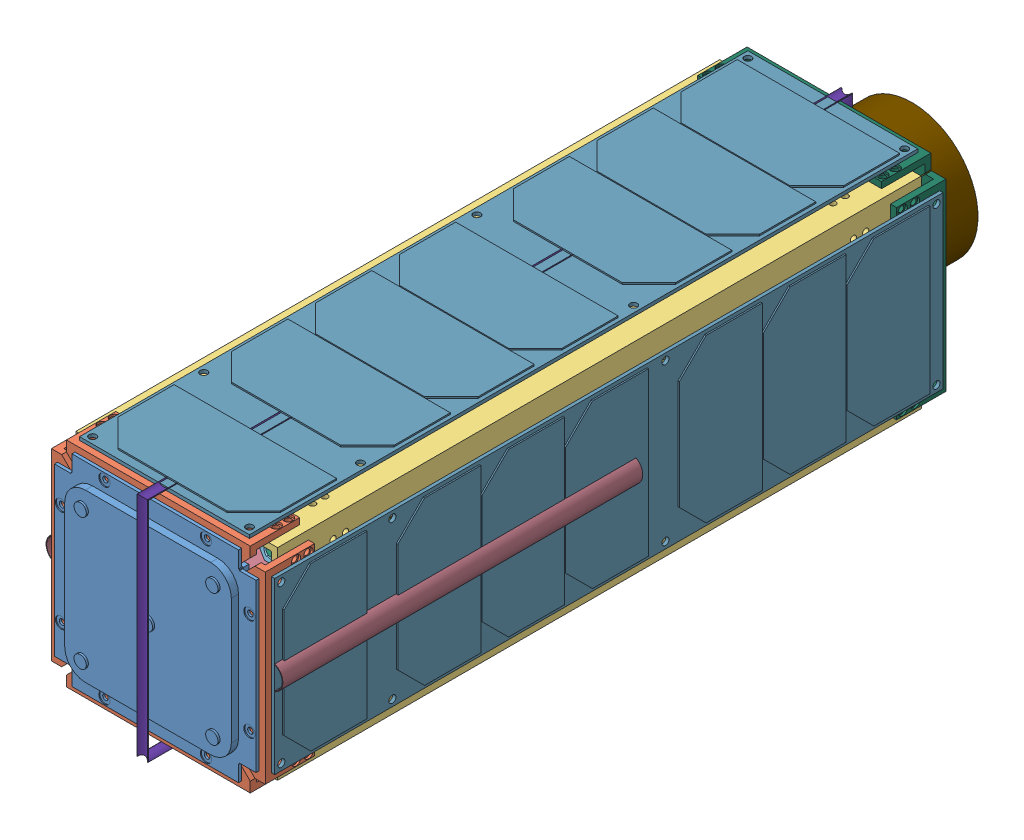
SolidWorks assembly RADIO Stowed, configuration Default. Lengths in mm.
Overall size (115.59 110.99 374.49).
77 component instances, 18 part files, 143 mates.
Components (placement in the parent):
- Nanocom Antenna-1: Nanocom Antenna [Default] at (54.7327 27.087 80.9297) size (98 98 11)
- Top Sipport-1: Top Sipport [Default] at (83.9034 50.4516 80.9297) x (0 -1 0) z (0 0 -1) size (89.4 11 24)
- Top Sipport-2: Top Sipport [Default] at (-15.8818 37.5538 80.9297) x (0 1 0) z (0 0 -1) size (89.4 11 24)
- Top Sipport-3: Top Sipport [Default] at (27.5619 93.8953 80.9297) x (1 0 0) z (0 0 -1) size (89.4 11 24)
- Top Sipport-4: Top Sipport [Default] at (40.4598 -5.8899 80.9297) x (-1 0 0) z (0 0 -1) size (89.4 11 24)
- Support-1: Support [Default] at (-14.9892 90.3455 -221.7132) x (0 -1 0) z (1 0 0) size (18 313 15)
- Support-2: Support [Default] at (-12.332 -4.9973 -221.7132) x (1 0 0) z (0 1 0) size (18 313 15)
- Support-3: Support [Default] at (80.3537 93.0027 -221.7132) x (-1 0 0) z (0 -1 0) size (18 313 15)
- Support-4: Support [Default] at (83.0108 -2.3402 -221.7132) x (0 1 0) z (-1 0 0) size (18 313 15)
- Top Plate2-1: Top Plate2 [Default] at (13.317 21.6849 56.9297) x (-1 0 0) z (0 0 -1) size (92 92 23)
- Nut-1: Nut [Default] at (-1.4892 79.5027 56.9297) size (11.55 10 5.32)
- Nut-2: Nut [Default] at (69.5108 8.5027 56.9297) x (0.821931 0.569587 0) z (0 0 1) size (11.55 10 5.32)
- Nut-3: Nut [Default] at (69.5108 79.5027 56.9297) size (11.55 10 5.32)
- Nut-4: Nut [Default] at (-1.4892 8.5027 56.9297) size (11.55 10 5.32)
- Threaded Rod2-1: Threaded Rod2 [Default] at (69.5108 8.5027 -231.0703) size (6.4 7.01 294.26)
- Threaded Rod2-2: Threaded Rod2 [Default] at (-1.4892 8.5027 -231.0703) size (6.4 7.01 294.26)
- Threaded Rod2-3: Threaded Rod2 [Default] at (-1.4892 79.5027 -231.0703) size (6.4 7.01 294.26)
- Threaded Rod2-4: Threaded Rod2 [Default] at (69.5108 79.5027 -231.0703) size (6.4 7.01 294.26)
- Mid Plate-1: Mid Plate [Default] at (4.649 54.0261 25.9297) size (86 86 3)
- Nut-5: Nut [Default] at (-1.4892 8.5027 20.9297) x (0.999286 -0.037791 0) z (0 0 1) size (11.55 10 5.32)
- Nut-6: Nut [Default] at (-1.4892 8.5027 28.9297) size (11.55 10 5.32)
- Nut-7: Nut [Default] at (69.5108 8.5027 28.9297) size (11.55 10 5.32)
- Nut-8: Nut [Default] at (69.5108 8.5027 20.9297) x (0.921379 0.388666 0) z (0 0 1) size (11.55 10 5.32)
- Nut-9: Nut [Default] at (69.5108 79.5027 28.9297) size (11.55 10 5.32)
- Nut-10: Nut [Default] at (-1.4892 79.5027 28.9297) size (11.55 10 5.32)
- Nut-11: Nut [Default] at (69.5108 79.5027 20.9297) x (0.963517 0.267648 0) z (0 0 1) size (11.55 10 5.32)
- Nut-12: Nut [Default] at (-1.4892 79.5027 20.9297) x (0.997929 0.06432 0) z (0 0 1) size (11.55 10 5.32)
- SDR-1: SDR [Default] at (37.1692 34.198 30.9297) size (65 40 16.8)
- TTC Radio-1: TTC Radio [Default] at (48.3672 78.5027 28.9297) x (0 1 0) z (0 0 1) size (19.7 16 5)
- Raspberry Pi-1: Raspberry Pi [Default] at (63.5108 49.6464 -55.0703) size (66 30.48 5)
- TTC Circuit-1: TTC Circuit [Default] at (24.4431 25.9578 10.9297) size (80 50 10)
- Battery-1: Battery [Default] at (21.7415 31.358 -37.0703) size (70.1 42.59 38.1)
- Tape Antenna-3: Tape Antenna [Default] at (-17.3053 44.2096 -97.0703) x (-0.035253 -0.999378 0) z (0 0 1) size (11.67 4.21 175)
- Tape Antenna-4: Tape Antenna [Default] at (85.299 43.4652 -97.0703) x (0.030207 0.999544 0) z (0 0 1) size (11.67 4.21 175)
- Mid Plate-2: Mid Plate [Default] at (4.649 54.0261 7.9297) size (86 86 3)
- Nut-13: Nut [Default] at (-1.4892 8.5027 10.9297) size (11.55 10 5.32)
- Nut-14: Nut [Default] at (69.5108 79.5027 10.9297) size (11.55 10 5.32)
- Nut-15: Nut [Default] at (-1.4892 8.5027 2.9297) size (11.55 10 5.32)
- Nut-16: Nut [Default] at (-1.4892 79.5027 10.9297) size (11.55 10 5.32)
- Nut-17: Nut [Default] at (-1.4892 79.5027 2.9297) size (11.55 10 5.32)
- Nut-18: Nut [Default] at (69.5108 8.5027 2.9297) size (11.55 10 5.32)
- Nut-19: Nut [Default] at (69.5108 8.5027 10.9297) size (11.55 10 5.32)
- Nut-20: Nut [Default] at (69.5108 79.5027 2.9297) size (11.55 10 5.32)
- Mid Plate-3: Mid Plate [Default] at (4.649 54.0261 -40.0703) size (86 86 3)
- Nut-21: Nut [Default] at (69.5108 79.5027 -37.0703) size (11.55 10 5.32)
- Nut-22: Nut [Default] at (-1.4892 8.5027 -40.0703) x (-0.923728 -0.383049 0) z (0 0 -1) size (11.55 10 5.32)
- Nut-23: Nut [Default] at (-1.4892 79.5027 -40.0703) x (-0.923728 -0.383049 0) z (0 0 -1) size (11.55 10 5.32)
- Nut-24: Nut [Default] at (69.5108 8.5027 -37.0703) size (11.55 10 5.32)
- Nut-25: Nut [Default] at (69.5108 79.5027 -40.0703) x (-0.923728 -0.383049 0) z (0 0 -1) size (11.55 10 5.32)
- Nut-26: Nut [Default] at (69.5108 8.5027 -40.0703) x (-0.923728 -0.383049 0) z (0 0 -1) size (11.55 10 5.32)
- Nut-27: Nut [Default] at (-1.4892 8.5027 -37.0703) size (11.55 10 5.32)
- Nut-28: Nut [Default] at (-1.4892 79.5027 -37.0703) size (11.55 10 5.32)
- Nut-29: Nut [Default] at (-1.4892 8.5027 -63.0703) size (11.55 10 5.32)
- Nut-30: Nut [Default] at (69.5108 79.5027 -63.0703) size (11.55 10 5.32)
- Nut-31: Nut [Default] at (69.5108 8.5027 -63.0703) size (11.55 10 5.32)
- Nut-32: Nut [Default] at (-1.4892 8.5027 -55.0703) size (11.55 10 5.32)
- Nut-33: Nut [Default] at (-1.4892 79.5027 -55.0703) size (11.55 10 5.32)
- Nut-34: Nut [Default] at (69.5108 8.5027 -55.0703) size (11.55 10 5.32)
- Nut-35: Nut [Default] at (-1.4892 79.5027 -63.0703) size (11.55 10 5.32)
- Nut-36: Nut [Default] at (69.5108 79.5027 -55.0703) size (11.55 10 5.32)
- Mid Plate-4: Mid Plate [Default] at (4.649 54.0261 -58.0703) size (86 86 3)
- Top Plate2-2: Top Plate2 [Default] at (54.7047 21.6849 -226.0703) size (92 92 23)
- Nut-37: Nut [Default] at (69.5108 8.5027 -226.0703) x (-0.923728 -0.383049 0) z (0 0 -1) size (11.55 10 5.32)
- Nut-38: Nut [Default] at (69.5108 79.5027 -226.0703) x (-0.923728 -0.383049 0) z (0 0 -1) size (11.55 10 5.32)
- Nut-39: Nut [Default] at (-1.4892 8.5027 -226.0703) x (-0.923728 -0.383049 0) z (0 0 -1) size (11.55 10 5.32)
- Nut-40: Nut [Default] at (-1.4892 79.5027 -226.0703) x (-0.923728 -0.383049 0) z (0 0 -1) size (11.55 10 5.32)
- 3U Panel-1: 3U Panel [Default] at (-17.9892 -8.6653 1.9441) x (0 -1 0) z (-1 0 0) size (82.6 325 2.3)
- 3U Panel-5: 3U Panel [Default] at (86.6788 -7.9973 1.9441) x (1 0 0) z (0 -1 0) size (82.6 325 2.3)
- 3U Panel-6: 3U Panel [Default] at (86.0108 96.6707 1.9441) x (0 1 0) z (1 0 0) size (82.6 325 2.3)
- 3U Panel-7: 3U Panel [Default] at (-18.6571 96.0027 1.9441) x (-1 0 0) z (0 1 0) size (82.6 325 2.3)
- Top Support Solar Panel-1: Top Support Solar Panel [Default] at (27.5619 -3.8899 -250.0703) size (89.4 13 24)
- Top Support Solar Panel-2: Top Support Solar Panel [Default] at (81.9034 37.5538 -250.0703) x (0 1 0) z (0 0 1) size (89.4 13 24)
- Top Support Solar Panel-3: Top Support Solar Panel [Default] at (40.4598 91.8953 -250.0703) x (-1 0 0) z (0 0 1) size (89.4 13 24)
- Top Support Solar Panel-4: Top Support Solar Panel [Default] at (-13.8818 50.4516 -250.0703) x (0 -1 0) z (0 0 1) size (89.4 13 24)
- 1U Panel-1: 1U Panel [Default] at (10.1282 49.1305 -250.0703) x (-1 0 0) z (0 0 -1) size (98 98 2.3)
- Undeployed Boom-1: Undeployed Boom [Default] at (33.6808 70.7812 -106.8653) x (0 0 -1) z (1 0 0) size (342.69 110.69 5.53)
- Mass-1: Mass [Default] at (33.6036 44.7293 -286.0703) size (64 64 36)
Mates (geometry in assembly coordinates):
- Coincident1: coincident: circle of Nanocom Antenna-1; circle of Top Sipport-4
- Coincident2: coincident: circle of Nanocom Antenna-1; circle of Top Sipport-4
- Coincident3: coincident: circle of Nanocom Antenna-1; circle of Top Sipport-2
- Coincident4: coincident: circle of Nanocom Antenna-1; circle of Top Sipport-2
- Coincident5: coincident: circle of Nanocom Antenna-1; circle of Top Sipport-3
- Coincident6: coincident: circle of Nanocom Antenna-1; circle of Top Sipport-3
- Coincident7: coincident: circle of Nanocom Antenna-1; circle of Top Sipport-1
- Coincident8: coincident: circle of Nanocom Antenna-1; circle of Top Sipport-1
- Coincident9: coincident: circle of Top Sipport-2; circle of Support-1
- Coincident10: coincident: circle of Top Sipport-3; circle of Support-1
- Coincident11: coincident: circle of Top Sipport-3; circle of Support-3
- Coincident12: coincident: circle of Top Sipport-1; circle of Support-3
- Coincident13: coincident: circle of Top Sipport-2; circle of Support-2
- Coincident14: coincident: circle of Top Sipport-4; circle of Support-2
- Coincident16: coincident: circle of Top Sipport-4; circle of Support-4
- Coincident17: coincident: circle of Top Sipport-1; circle of Support-4
- Coincident20: coincident: circle of Support-1; circle of Top Plate2-1
- Coincident21: coincident: circle of Support-2; circle of Top Plate2-1
- Coincident22: coincident: circle of Top Plate2-1; circle of Nut-3
- Coincident23: coincident: circle of Top Plate2-1; circle of Nut-1
- Coincident24: coincident: circle of Top Plate2-1; circle of Nut-4
- Coincident25: coincident: circle of Top Plate2-1; circle of Nut-2
- Concentric1: concentric: circle of Top Plate2-1; circle of Threaded Rod2-1
- Coincident26: coincident: plane of Nut-2 through (69.5108 8.5027 61.9297) normal (0 0 1); plane of Threaded Rod2-1 through (69.5108 8.5027 61.9297) normal (0 0 1)
- Concentric2: concentric: circle of Top Plate2-1; circle of Threaded Rod2-4
- Coincident27: coincident: plane of Nut-3 through (69.5108 79.5027 61.9297) normal (0 0 1); plane of Threaded Rod2-4 through (69.5108 79.5027 61.9297) normal (0 0 1)
- Concentric3: concentric: circle of Top Plate2-1; circle of Threaded Rod2-2
- Coincident28: coincident: plane of Nut-4 through (-1.4892 8.5027 61.9297) normal (0 0 1); plane of Threaded Rod2-2 through (-1.4892 8.5027 61.9297) normal (0 0 1)
- Concentric4: concentric: circle of Top Plate2-1; circle of Threaded Rod2-3
- Coincident29: coincident: plane of Nut-1 through (-1.4892 79.5027 61.9297) normal (0 0 1); plane of Threaded Rod2-3 through (-1.4892 79.5027 61.9297) normal (0 0 1)
- Concentric5: concentric: circle of Threaded Rod2-4; circle of Mid Plate-1
- Concentric6: concentric: circle of Threaded Rod2-2; circle of Mid Plate-1
- Concentric7: concentric: circle of Threaded Rod2-2; circle of Nut-6
- Coincident30: coincident: plane of Mid Plate-1 through (4.649 54.0261 28.9297) normal (0 0 1); plane of Nut-6 through (-1.4892 8.5027 28.9297) normal (0 0 -1)
- Concentric8: concentric: circle of Threaded Rod2-2; circle of Nut-5
- Coincident31: coincident: plane of Mid Plate-1 through (4.649 54.0261 25.9297) normal (0 0 -1); plane of Nut-5 through (-1.4892 8.5027 25.9297) normal (0 0 1)
- Concentric9: concentric: circle of Threaded Rod2-1; circle of Nut-7
- Coincident32: coincident: plane of Mid Plate-1 through (4.649 54.0261 28.9297) normal (0 0 1); plane of Nut-7 through (69.5108 8.5027 28.9297) normal (0 0 -1)
- Concentric10: concentric: circle of Threaded Rod2-1; circle of Nut-8
- Coincident33: coincident: plane of Mid Plate-1 through (4.649 54.0261 25.9297) normal (0 0 -1); plane of Nut-8 through (69.5108 8.5027 25.9297) normal (0 0 1)
- Concentric11: concentric: circle of Threaded Rod2-4; circle of Nut-9
- Coincident34: coincident: plane of Mid Plate-1 through (4.649 54.0261 28.9297) normal (0 0 1); plane of Nut-9 through (69.5108 79.5027 28.9297) normal (0 0 -1)
- Concentric12: concentric: circle of Threaded Rod2-3; circle of Nut-10
- Coincident35: coincident: plane of Mid Plate-1 through (4.649 54.0261 28.9297) normal (0 0 1); plane of Nut-10 through (-1.4892 79.5027 28.9297) normal (0 0 -1)
- Concentric13: concentric: circle of Threaded Rod2-4; circle of Nut-11
- Coincident36: coincident: plane of Mid Plate-1 through (4.649 54.0261 25.9297) normal (0 0 -1); plane of Nut-11 through (69.5108 79.5027 25.9297) normal (0 0 1)
- Concentric14: concentric: circle of Threaded Rod2-3; circle of Nut-12
- Coincident37: coincident: plane of Mid Plate-1 through (4.649 54.0261 25.9297) normal (0 0 -1); plane of Nut-12 through (-1.4892 79.5027 25.9297) normal (0 0 1)
- Distance1: distance = 25 mm: plane of Mid Plate-1 through (4.649 54.0261 28.9297) normal (0 0 1); plane of Top Plate2-1 through (13.317 21.6849 53.9297) normal (0 0 -1)
- Coincident39: coincident: plane of Mid Plate-1 through (4.649 54.0261 28.9297) normal (0 0 1); plane of SDR-1 through (37.1692 34.198 28.9297) normal (0 0 -1)
- Distance4: distance = 12 mm: line of SDR-1 through (65.0108 16.0027 28.9297) axis (0 1 0); line of Mid Plate-1 through (77.0108 4.0027 28.9297) axis (0 1 0)
- Distance5: distance = 15 mm: line of SDR-1 through (0.0108 16.0027 28.9297) axis (1 0 0); line of Mid Plate-1 through (-5.9892 1.0027 28.9297) axis (1 0 0)
- Coincident46: coincident: plane of Mid Plate-1 through (4.649 54.0261 28.9297) normal (0 0 1); plane of TTC Radio-1 through (48.3672 78.5027 28.9297) normal (0 0 -1)
- Distance8: distance = 20 mm: plane of TTC Radio-1 through (57.0108 78.5027 30.9297) normal (1 0 0); plane of Mid Plate-1 through (77.0108 4.0027 28.9297) normal (1 0 0)
- Distance9: distance = 5 mm: plane of TTC Radio-1 through (48.3672 82.0027 30.9297) normal (0 1 0); line of Mid Plate-1 through (74.0108 87.0027 28.9297) axis (-1 0 0)
- Coincident53: coincident: plane of TTC Circuit-1 through (24.4431 25.9578 10.9297) normal (0 0 -1); plane of Mid Plate-2 through (4.649 54.0261 10.9297) normal (0 0 1)
- Distance10: distance = 5 mm: line of TTC Circuit-1 through (-4.4066 66.0027 12.9297) axis (0 -1 0); line of Mid Plate-2 through (-8.9892 84.0027 10.9297) axis (0 -1 0)
- Distance13: distance = 21.095 mm: line of TTC Circuit-1 through (75.5934 66.0027 12.9297) axis (-1 0 0); line of Mid Plate-2 through (74.0108 87.0027 10.9297) axis (-1 0 0)
- Concentric16: concentric: circle of Threaded Rod2-2; circle of Mid Plate-2
- Concentric18: concentric: circle of Threaded Rod2-4; circle of Mid Plate-2
- Concentric19: concentric: circle of Threaded Rod2-4; circle of Nut-14
- Coincident59: coincident: plane of Mid Plate-2 through (4.649 54.0261 10.9297) normal (0 0 1); plane of Nut-14 through (69.5108 79.5027 10.9297) normal (0 0 -1)
- Concentric20: concentric: circle of Threaded Rod2-4; circle of Nut-20
- Coincident60: coincident: plane of Mid Plate-2 through (4.649 54.0261 7.9297) normal (0 0 -1); plane of Nut-20 through (69.5108 79.5027 7.9297) normal (0 0 1)
- Concentric21: concentric: circle of Threaded Rod2-1; circle of Nut-19
- Coincident61: coincident: plane of Mid Plate-2 through (4.649 54.0261 10.9297) normal (0 0 1); plane of Nut-19 through (69.5108 8.5027 10.9297) normal (0 0 -1)
- Concentric22: concentric: circle of Threaded Rod2-1; circle of Nut-18
- Coincident62: coincident: plane of Mid Plate-2 through (4.649 54.0261 7.9297) normal (0 0 -1); plane of Nut-18 through (69.5108 8.5027 7.9297) normal (0 0 1)
- Concentric23: concentric: circle of Threaded Rod2-2; circle of Nut-13
- Coincident63: coincident: plane of Mid Plate-2 through (4.649 54.0261 10.9297) normal (0 0 1); plane of Nut-13 through (-1.4892 8.5027 10.9297) normal (0 0 -1)
- Concentric24: concentric: circle of Threaded Rod2-2; circle of Nut-15
- Coincident64: coincident: plane of Mid Plate-2 through (4.649 54.0261 7.9297) normal (0 0 -1); plane of Nut-15 through (-1.4892 8.5027 7.9297) normal (0 0 1)
- Concentric25: concentric: circle of Threaded Rod2-3; circle of Nut-16
- Coincident65: coincident: plane of Mid Plate-2 through (4.649 54.0261 10.9297) normal (0 0 1); plane of Nut-16 through (-1.4892 79.5027 10.9297) normal (0 0 -1)
- Concentric26: concentric: circle of Threaded Rod2-3; circle of Nut-17
- Coincident66: coincident: plane of Mid Plate-2 through (4.649 54.0261 7.9297) normal (0 0 -1); plane of Nut-17 through (-1.4892 79.5027 7.9297) normal (0 0 1)
- Distance14: distance = 15 mm: plane of Mid Plate-2 through (4.649 54.0261 10.9297) normal (0 0 1); plane of Mid Plate-1 through (4.649 54.0261 25.9297) normal (0 0 -1)
- Coincident68: coincident: circle of Mid Plate-3; circle of Nut-21
- Coincident69: coincident: circle of Mid Plate-3; circle of Nut-24
- Coincident70: coincident: circle of Mid Plate-3; circle of Nut-27
- Coincident71: coincident: circle of Mid Plate-3; circle of Nut-28
- Coincident72: coincident: circle of Mid Plate-3; circle of Nut-25
- Coincident73: coincident: circle of Mid Plate-3; circle of Nut-23
- Coincident74: coincident: circle of Mid Plate-3; circle of Nut-22
- Coincident76: coincident: circle of Mid Plate-3; circle of Nut-26
- Coincident77: coincident: plane of Battery-1 through (21.7415 31.358 -37.0703) normal (0 0 -1); plane of Mid Plate-3 through (4.649 54.0261 -37.0703) normal (0 0 1)
- Distance16: distance = 30 mm: line of Battery-1 through (57.8687 57.4223 -32.0703) axis (-1 0 0); line of Mid Plate-3 through (74.0108 87.0027 -37.0703) axis (-1 0 0)
- Distance17: distance = 15 mm: line of Battery-1 through (62.8687 24.8323 -32.0703) axis (0 1 0); line of Mid Plate-3 through (77.0108 4.0027 -37.0703) axis (0 1 0)
- Concentric27: concentric: circle of Threaded Rod2-2; circle of Nut-27
- Concentric28: concentric: circle of Threaded Rod2-4; circle of Nut-21
- Distance18: distance = 45 mm: plane of Mid Plate-3 through (4.649 54.0261 -37.0703) normal (0 0 1); plane of Mid Plate-2 through (4.649 54.0261 7.9297) normal (0 0 -1)
- Coincident83: coincident: plane of Raspberry Pi-1 through (63.5108 49.6464 -55.0703) normal (0 0 -1); plane of Mid Plate-4 through (4.649 54.0261 -55.0703) normal (0 0 1)
- Distance19: distance = 30 mm: line of Raspberry Pi-1 through (67.0108 57.0027 -55.0703) axis (-1 0 0); line of Mid Plate-4 through (74.0108 87.0027 -55.0703) axis (-1 0 0)
- Distance20: distance = 10 mm: line of Raspberry Pi-1 through (67.0108 26.5227 -55.0703) axis (0 1 0); line of Mid Plate-4 through (77.0108 4.0027 -55.0703) axis (0 1 0)
- Concentric29: concentric: circle of Nut-29; circle of Mid Plate-4
- Coincident87: coincident: plane of Nut-29 through (-1.4892 8.5027 -58.0703) normal (0 0 1); plane of Mid Plate-4 through (4.649 54.0261 -58.0703) normal (0 0 -1)
- Concentric30: concentric: circle of Nut-31; circle of Mid Plate-4
- Coincident89: coincident: plane of Nut-31 through (69.5108 8.5027 -58.0703) normal (0 0 1); plane of Mid Plate-4 through (4.649 54.0261 -58.0703) normal (0 0 -1)
- Concentric31: concentric: circle of Nut-30; circle of Mid Plate-4
- Coincident91: coincident: plane of Nut-30 through (69.5108 79.5027 -58.0703) normal (0 0 1); plane of Mid Plate-4 through (4.649 54.0261 -58.0703) normal (0 0 -1)
- Concentric32: concentric: circle of Nut-35; circle of Mid Plate-4
- Coincident93: coincident: plane of Nut-35 through (-1.4892 79.5027 -58.0703) normal (0 0 1); plane of Mid Plate-4 through (4.649 54.0261 -58.0703) normal (0 0 -1)
- Coincident94: coincident: circle of Nut-33; circle of Mid Plate-4
- Coincident95: coincident: circle of Nut-32; circle of Mid Plate-4
- Coincident96: coincident: circle of Nut-36; circle of Mid Plate-4
- Coincident97: coincident: circle of Nut-34; circle of Mid Plate-4
- Concentric33: concentric: circle of Threaded Rod2-2; circle of Nut-29
- Concentric34: concentric: circle of Threaded Rod2-3; circle of Nut-35
- Distance21: distance = 15 mm: plane of Mid Plate-4 through (4.649 54.0261 -55.0703) normal (0 0 1); plane of Mid Plate-3 through (4.649 54.0261 -40.0703) normal (0 0 -1)
- Coincident100: coincident: circle of Top Plate2-2; circle of Nut-37
- Coincident101: coincident: circle of Top Plate2-2; circle of Nut-39
- Coincident102: coincident: circle of Top Plate2-2; circle of Nut-38
- Coincident103: coincident: circle of Top Plate2-2; circle of Nut-40
- Concentric35: concentric: circle of Threaded Rod2-3; circle of Top Plate2-2
- Concentric36: concentric: circle of Threaded Rod2-4; circle of Top Plate2-2
- Coincident104: coincident: plane of Threaded Rod2-4 through (69.5108 79.5027 -231.0703) normal (0 0 -1); plane of Nut-38 through (69.5108 79.5027 -231.0703) normal (0 0 -1)
- Coincident123: coincident: circle of Top Sipport-2; circle of 3U Panel-1
- Coincident124: coincident: circle of Top Sipport-2; circle of 3U Panel-1
- Coincident125: coincident: circle of Top Sipport-4; circle of 3U Panel-5
- Coincident126: coincident: circle of Top Sipport-4; circle of 3U Panel-5
- Coincident127: coincident: circle of Top Sipport-3; circle of 3U Panel-7
- Coincident128: coincident: circle of Top Sipport-3; circle of 3U Panel-7
- Coincident129: coincident: circle of Top Sipport-1; circle of 3U Panel-6
- Coincident130: coincident: circle of Top Sipport-1; circle of 3U Panel-6
- Coincident131: coincident: point of Tape Antenna-4; line of 3U Panel-6 through (87.6108 85.3027 77.9297) axis (0 -1 0)
- Coincident132: coincident: point of Tape Antenna-4; line of 3U Panel-6 through (87.6108 85.3027 77.9297) axis (0 -1 0)
- Parallel16: parallel: line of Support-4 through (83.0108 -4.9973 -241.0703) axis (0 0 1); line of Tape Antenna-4 through (87.7209 37.6494 77.9297) axis (0 0 -1)
- Coincident137: coincident: point of Tape Antenna-3; line of 3U Panel-1 through (-19.5892 2.7027 77.9297) axis (0 1 0)
- Coincident138: coincident: point of Tape Antenna-3; line of 3U Panel-1 through (-19.5892 2.7027 77.9297) axis (0 1 0)
- Parallel19: parallel: line of Tape Antenna-3 through (-19.6978 50.0375 77.9297) axis (0 0 -1); line of 3U Panel-1 through (-19.5892 85.3027 77.9297) axis (0 0 -1)
- Coincident140: coincident: circle of 3U Panel-6; circle of Top Support Solar Panel-2
- Coincident141: coincident: circle of 3U Panel-6; circle of Top Support Solar Panel-2
- Coincident142: coincident: circle of 3U Panel-5; circle of Top Support Solar Panel-1
- Coincident143: coincident: circle of 3U Panel-5; circle of Top Support Solar Panel-1
- Coincident144: coincident: circle of 3U Panel-1; circle of Top Support Solar Panel-4
- Coincident145: coincident: circle of 3U Panel-1; circle of Top Support Solar Panel-4
- Coincident146: coincident: circle of 3U Panel-7; circle of Top Support Solar Panel-3
- Coincident147: coincident: circle of 3U Panel-7; circle of Top Support Solar Panel-3
- Coincident148: coincident: circle of Top Support Solar Panel-3; circle of 1U Panel-1
- Coincident149: coincident: circle of Top Support Solar Panel-1; circle of 1U Panel-1
- Parallel20: parallel: line of Support-3 through (83.0108 93.0027 -241.0703) axis (0 0 1); line of Undeployed Boom-1 through (30.9528 97.7265 -106.8653) axis (0 0 -1)
- Tangent4: tangent: cylinder of Undeployed Boom-1 through (33.6808 -12.8247 90.615) axis (0 1 0) radius 3.6853; plane of Nanocom Antenna-1 through (34.0108 44.0027 86.9297) normal (0 0 1)
- Coincident152: coincident: plane of 1U Panel-1 through (10.1282 49.1305 -250.0703) normal (0 0 1); plane of Mass-1 through (33.6036 44.7293 -250.0703) normal (0 0 1)
